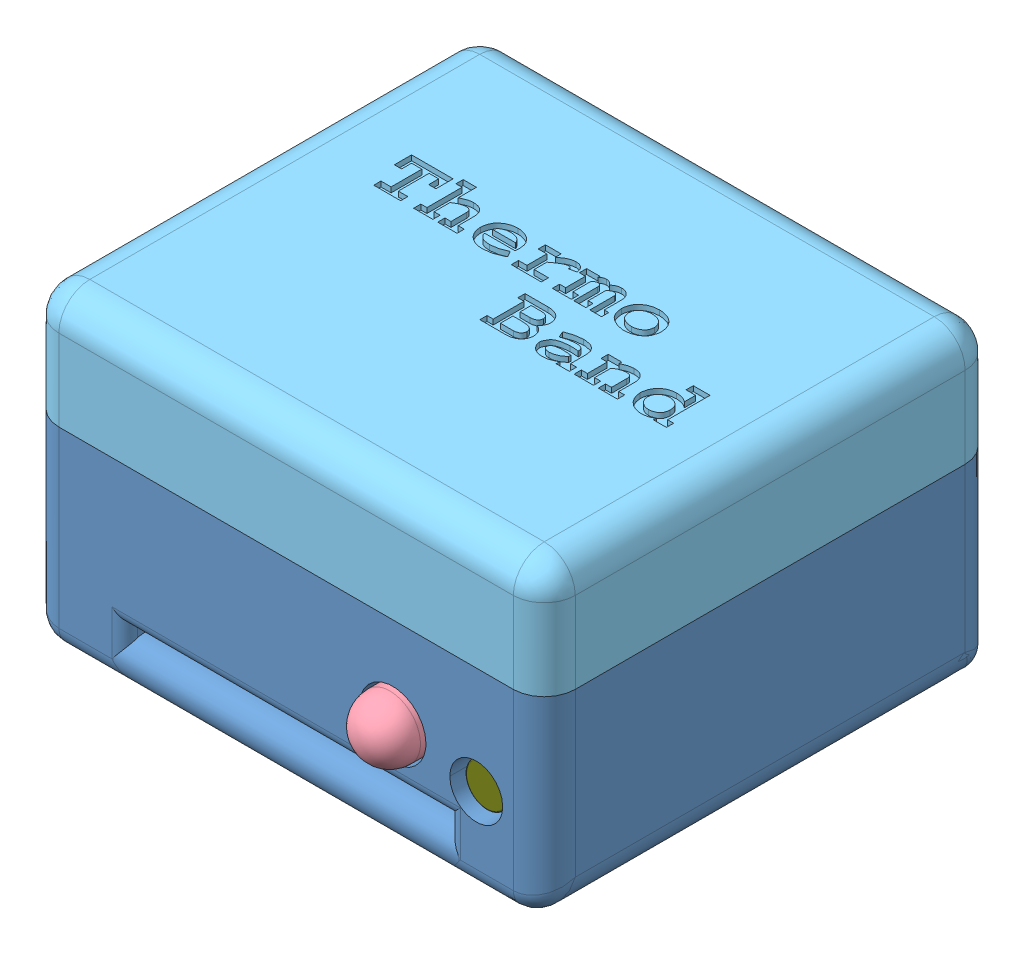
SolidWorks assembly Assembly, configuration Default. Lengths in mm.
Overall size (40 24.24 37.6).
114 component instances, 28 part files, 12 mates.
Components (placement in the parent):
- Housing-1: Housing [Default] at origin size (40 17 35.02)
- DS18B20-1: DS18B20 [Default] at (2.1825 -0.25 0.0476) x (0 0 -1) z (0 1 0) size (4.58 19.05 3.56)
- Battery-1: Battery [Default] at (-0.5 5.02 -1.5) size (35 8 20)
- Circuit Assembly-1: Circuit Assembly [Default] at (-15.4099 -5.9263 -30.8091) x (1 0 0) z (0 0 1) size (37.22 34.92 34.2)
  - PowerBoard.step-1: PowerBoard.step [Default] at (-2.5901 17.3095 38.1523) x (1 0 0) z (0 1 0) size (37.14 20 34.92)
    - Board_Power.step-1: Board_Power.step [Default] at origin size (36 20 0.91)
      - Open CASCADE STEP translator 7.5 1.1.1.step-1: Open CASCADE STEP translator 7.5 1.1.1.step [Default] at (0 0 -0.9132) size (36 20 0.91)
    - V1_Power.step-1: V1_Power.step [Default] at origin size (2.8 2.9 1.45)
      - 6479615344.step-1: 6479615344.step [Default] at (29.07 5.49 -0.9132) x (1 0 0) z (0 1 0) size (2.8 1.45 2.9)
    - R9_Power.step-1: R9_Power.step [Default] at origin size (1.45 2.15 0.71)
      - RES_CRGCQ0805F1K2_TEC.step-1: RES_CRGCQ0805F1K2_TEC.step [Default] at (33.56 5.72 -0.9132) x (0 1 0) z (0 0 -1) size (2.15 1.45 0.71)
    - C6_Power.step-1: C6_Power.step [Default] at origin size (2.15 1.45 0.71)
      - RES_CRGCQ0805F1K2_TEC.step-1: RES_CRGCQ0805F1K2_TEC.step [Default] at (28.99 2.19 -0.9132) x (-1 0 0) z (0 0 -1) size (2.15 1.45 0.71)
    - C5_Power.step-1: C5_Power.step [Default] at origin size (2.15 1.45 0.71)
      - RES_CRGCQ0805F1K2_TEC.step-1: RES_CRGCQ0805F1K2_TEC.step [Default] at (32.72 1.75 -0.9132) x (-1 0 0) z (0 0 -1) size (2.15 1.45 0.71)
    - P1_Power.step-1: P1_Power.step [Default] at origin size (6.87 8.94 4.22)
      - USB Connector Type C female 6pin.step-1: USB Connector Type C female 6pin.step [Default] at (-1.142 5.41 1.618) x (0 -1 0) z (-1 0 0) size (8.94 4.22 6.87)
    - Q1_Power.step-1: Q1_Power.step [Default] at origin size (10.41 4.45 29.34) (hidden)
      - 6479615824.step-1: 6479615824.step [Default] at (30.19 17.34 0) x (1 0 0) z (0 -1 0) size (10.41 29.34 4.45)
        - IRF9540N.step-1: IRF9540N.step [Default] at (-2.54 0 0.8128) size (10.41 29.34 4.45)
    - H2_Power.step-1: H2_Power.step [Default] at origin size (10.16 10.22 4.7)
      - 10129379-904002BLF.step-1: 10129379-904002BLF.step [Default] at (26.56 8.431 1.2177) x (0 -1 0) z (0 0 -1) size (10.22 10.16 4.7)
    - R8_Power.step-1: R8_Power.step [Default] at origin size (2.15 1.45 0.71)
      - RES_CRGCQ0805F1K2_TEC.step-1: RES_CRGCQ0805F1K2_TEC.step [Default] at (29.3 13.35 0) x (-1 0 0) z (0 0 1) size (2.15 1.45 0.71)
    - R7_Power.step-1: R7_Power.step [Default] at origin size (1.45 2.15 0.71)
      - RES_CRGCQ0805F1K2_TEC.step-1: RES_CRGCQ0805F1K2_TEC.step [Default] at (14.4 12.165 0) x (0 1 0) z (0 0 1) size (2.15 1.45 0.71)
    - R6_Power.step-1: R6_Power.step [Default] at origin size (1.45 2.15 0.71)
      - RES_CRGCQ0805F1K2_TEC.step-1: RES_CRGCQ0805F1K2_TEC.step [Default] at (23.1 17.5 0) x (0 1 0) z (0 0 1) size (2.15 1.45 0.71)
    - R5_Power.step-1: R5_Power.step [Default] at origin size (2.15 1.45 0.71)
      - RES_CRGCQ0805F1K2_TEC.step-1: RES_CRGCQ0805F1K2_TEC.step [Default] at (16.6 1.8 0) size (2.15 1.45 0.71)
    - R4_Power.step-1: R4_Power.step [Default] at origin size (2.15 1.45 0.71)
      - RES_CRGCQ0805F1K2_TEC.step-1: RES_CRGCQ0805F1K2_TEC.step [Default] at (8.28 10.59 -0.9132) x (-1 0 0) z (0 0 -1) size (2.15 1.45 0.71)
    - R3_Power.step-1: R3_Power.step [Default] at origin size (1.45 2.15 0.71)
      - RES_CRGCQ0805F1K2_TEC.step-1: RES_CRGCQ0805F1K2_TEC.step [Default] at (5.8 14.835 0) x (0 1 0) z (0 0 1) size (2.15 1.45 0.71)
    - R2_Power.step-1: R2_Power.step [Default] at origin size (1.45 2.15 0.71)
      - RES_CRGCQ0805F1K2_TEC.step-1: RES_CRGCQ0805F1K2_TEC.step [Default] at (8 14.865 0) x (0 1 0) z (0 0 1) size (2.15 1.45 0.71)
    - R1_Power.step-1: R1_Power.step [Default] at origin size (1.45 2.15 0.71)
      - RES_CRGCQ0805F1K2_TEC.step-1: RES_CRGCQ0805F1K2_TEC.step [Default] at (14.6 8.4 0) x (0 1 0) z (0 0 1) size (2.15 1.45 0.71)
    - Q3_Power.step-1: Q3_Power.step [Default] at origin size (4.76 3.63 20.95) (hidden)
      - 6470186752.step-1: 6470186752.step [Default] at (18.7734 17.507 0) x (1 0 0) z (0 -1 0) size (4.76 20.95 3.63)
        - KSC1008YBU_KSC1008YBU.step-1: KSC1008YBU_KSC1008YBU.step [Default] at (0 0 0.38) size (4.76 20.95 3.63)
    - Q2_Power.step-1: Q2_Power.step [Default] at origin size (4.76 3.63 20.95) (hidden)
      - 6470186672.step-1: 6470186672.step [Default] at (18.1966 12.903 0) x (-1 0 0) z (0 1 0) size (4.76 20.95 3.63)
        - KSC1008YBU_KSC1008YBU-0.step-1: KSC1008YBU_KSC1008YBU-0.step [Default] at (0 0 0.38) size (4.76 20.95 3.63)
    - M1_Power.step-1: M1_Power.step [Default] at origin size (3 4.5 1.05)
      - 6667053168.step-1: 6667053168.step [Default] at (22.835 8.51 0.15) size (3 4.5 1.05)
        - Extruded.step-1: Extruded.step [Default] at origin size (3 4.5 1.05)
    - IC2_Power.step-1: IC2_Power.step [Default] at origin size (1.8 3.1 1.3)
      - 6667052928.step-1: 6667052928.step [Default] at (18.025 8.6 0.15) size (1.8 3.1 1.3)
        - Extruded-1.step-1: Extruded-1.step [Default] at origin size (1.8 3.1 1.3)
    - IC1_Power.step-1: IC1_Power.step [Default] at origin size (4.33 4.9 1.1)
      - 6470186912.step-1: 6470186912.step [Default] at (11 14.85 0) x (0 1 0) z (0 0 1) size (4.9 4.33 1.1)
        - Body.step-1: Body.step [Default] at (-1.55 -1.55 0) size (3.1 3.1 0.95)
          - Open CASCADE STEP translator 7.5 1.2.1.step-1: Open CASCADE STEP translator 7.5 1.2.1.step [Default] at origin size (3.1 3.1 0.95)
        - Open CASCADE STEP translator 7.5 1.1.step-1: Open CASCADE STEP translator 7.5 1.1.step [Default] at (-1.55 -1.55 0.001) size (0.4 0.4 0.01)
        - Leader.step-1: Leader.step [Default] at (-1.55 -0.975 0) x (-1 0 0) z (0 0 1) size (1.25 0.32 1.05)
        - Leader.step-2: Leader.step [Default] at (-1.55 -0.325 0) x (-1 0 0) z (0 0 1) size (1.25 0.32 1.05)
        - Leader.step-3: Leader.step [Default] at (-1.55 0.325 0) x (-1 0 0) z (0 0 1) size (1.25 0.32 1.05)
        - Leader.step-4: Leader.step [Default] at (-1.55 0.975 0) x (-1 0 0) z (0 0 1) size (1.25 0.32 1.05)
        - Leader.step-5: Leader.step [Default] at (1.55 -0.975 0) size (1.25 0.32 1.05)
        - Leader.step-6: Leader.step [Default] at (1.55 -0.325 0) size (1.25 0.32 1.05)
        - Leader.step-7: Leader.step [Default] at (1.55 0.325 0) size (1.25 0.32 1.05)
        - Leader.step-8: Leader.step [Default] at (1.55 0.975 0) size (1.25 0.32 1.05)
    - C4_Power.step-1: C4_Power.step [Default] at origin size (1.45 2.15 0.71)
      - RES_CRGCQ0805F1K2_TEC.step-1: RES_CRGCQ0805F1K2_TEC.step [Default] at (8.14 7.57 -0.9132) x (0 1 0) z (0 0 -1) size (2.15 1.45 0.71)
    - C3_Power.step-1: C3_Power.step [Default] at origin size (2.59 3.99 8.21)
      - K104K15X7RF5TL2_VIS.step-1: K104K15X7RF5TL2_VIS.step [Default] at (8.05 2.314 0.3048) x (0 1 0) z (0 0 1) size (3.99 2.59 8.21)
    - C2_Power.step-1: C2_Power.step [Default] at origin size (1.45 2.15 0.71)
      - RES_CRGCQ0805F1K2_TEC.step-1: RES_CRGCQ0805F1K2_TEC.step [Default] at (12.08 2.09 -0.9132) x (0 1 0) z (0 0 -1) size (2.15 1.45 0.71)
    - C1_Power.step-1: C1_Power.step [Default] at origin size (2.59 3.99 8.21)
      - K104K15X7RF5TL2_VIS.step-1: K104K15X7RF5TL2_VIS.step [Default] at (11.8 5.254 0.3048) x (0 1 0) z (0 0 1) size (3.99 2.59 8.21)
  - SensorPCB.step-1: SensorPCB.step [Default] at (-2.5091 6.1912 41.4964) x (1 0 0) z (0 0 1) size (35.93 17.82 18.09)
    - Board_Sensor.step-1: Board_Sensor.step [Default] at origin size (28.7 17.82 0.91)
      - Open CASCADE STEP translator 7.5 2.1.1.step-1: Open CASCADE STEP translator 7.5 2.1.1.step [Default] at (0 0 -0.9132) size (28.7 17.82 0.91)
    - S2_Sensor.step-1: S2_Sensor.step [Default] at origin size (6 7.9 9.5)
      - 7413577248.step-1: 7413577248.step [Default] at (32.65 4.45 0) x (0 -1 0) z (-1 0 0) size (7.9 9.5 6)
    - S1_Sensor.step-1: S1_Sensor.step [Default] at origin size (3 4.5 1.05)
      - 6479614144.step-1: 6479614144.step [Default] at (12.34 9.02 -2.0132) size (3 4.5 1.05)
        - Extruded.step-1: Extruded.step [Default] at origin size (3 4.5 1.05)
    - IC1_Sensor.step-1: IC1_Sensor.step [Default] at origin size (24 16 3.17)
      - ESP-12F--3DModel-STEP-305423.step-1: ESP-12F--3DModel-STEP-305423.step [Default] at (12.065 8.854 -0.0223) x (1 0 0) z (0 -1 0) size (24 3.17 16)
        - Board.step-1: Board.step [Default] at origin size (24 0.87 16)
        - Shield.step-1: Shield.step [Default] at (3.2 3.17 0) x (1 0 0) z (0 0 -1) size (15.01 2.3 12.11)
        - LED-0603H0.75.step-1: LED-0603H0.75.step [Default] at (-5.5 0.87 -5.3) x (0 0 -1) z (0 1 0) size (1.7 0.9 0.75)
    - H2_Sensor.step-1: H2_Sensor.step [Default] at origin size (10.67 2.54 11.71)
      - PPPC041LFBN-RC.step-1: PPPC041LFBN-RC.step [Default] at (30.35 12.29 -0.926) x (1 0 0) z (0 1 0) size (10.67 11.71 2.54)
        - PPPC021LFBN-RC_C04.step-1: PPPC021LFBN-RC_C04.step [Default] at origin size (10.67 8.51 2.54)
        - Pin - Gold.step-1: Pin - Gold.step [Default] at (-3.81 0 0) size (0.76 3.71 0.41)
        - Pin - Gold.step-2: Pin - Gold.step [Default] at (-1.27 0 0) size (0.76 3.71 0.41)
        - Pin - Gold.step-3: Pin - Gold.step [Default] at (1.27 0 0) size (0.76 3.71 0.41)
        - Pin - Gold.step-4: Pin - Gold.step [Default] at (3.81 0 0) size (0.76 3.71 0.41)
    - R7_Sensor.step-1: R7_Sensor.step [Default] at origin size (1.45 2.15 0.71)
      - RES_CRGCQ0805F1K2_TEC.step-1: RES_CRGCQ0805F1K2_TEC.step [Default] at (17.1 9.6 -0.9132) x (0 1 0) z (0 0 -1) size (2.15 1.45 0.71)
    - R6_Sensor.step-1: R6_Sensor.step [Default] at origin size (2.15 1.45 0.71)
      - RES_CRGCQ0805F1K2_TEC.step-1: RES_CRGCQ0805F1K2_TEC.step [Default] at (22.3 3.8 -0.9132) x (-1 0 0) z (0 0 -1) size (2.15 1.45 0.71)
    - R5_Sensor.step-1: R5_Sensor.step [Default] at origin size (2.15 1.45 0.71)
      - RES_CRGCQ0805F1K2_TEC.step-1: RES_CRGCQ0805F1K2_TEC.step [Default] at (21.3 6.6 -0.9132) x (-1 0 0) z (0 0 -1) size (2.15 1.45 0.71)
    - R4_Sensor.step-1: R4_Sensor.step [Default] at origin size (2.15 1.45 0.71)
      - RES_CRGCQ0805F1K2_TEC.step-1: RES_CRGCQ0805F1K2_TEC.step [Default] at (21.2 9.3 -0.9132) x (-1 0 0) z (0 0 -1) size (2.15 1.45 0.71)
    - R3_Sensor.step-1: R3_Sensor.step [Default] at origin size (2.15 1.45 0.71)
      - RES_CRGCQ0805F1K2_TEC.step-1: RES_CRGCQ0805F1K2_TEC.step [Default] at (13.965 13.1 -0.9132) x (-1 0 0) z (0 0 -1) size (2.15 1.45 0.71)
    - R2_Sensor.step-1: R2_Sensor.step [Default] at origin size (2.15 1.45 0.71)
      - RES_CRGCQ0805F1K2_TEC.step-1: RES_CRGCQ0805F1K2_TEC.step [Default] at (22.235 13 -0.9132) x (-1 0 0) z (0 0 -1) size (2.15 1.45 0.71)
    - R1_Sensor.step-1: R1_Sensor.step [Default] at origin size (2.15 1.45 0.71)
      - RES_CRGCQ0805F1K2_TEC.step-1: RES_CRGCQ0805F1K2_TEC.step [Default] at (11.5 5 -0.9132) x (-1 0 0) z (0 0 -1) size (2.15 1.45 0.71)
    - H1_Sensor.step-1: H1_Sensor.step [Default] at origin size (7.62 2.54 11.68) (hidden)
      - M20-9990345_asm.step-1: M20-9990345_asm.step [Default] at (34.43 15.83 2.5526) x (-1 0 0) z (0 1 0) size (7.62 11.68 2.54)
        - M20-9990345_asm-1.step-1: M20-9990345_asm-1.step [Default] at origin size (7.62 11.68 2.54)
          - M20-999-MOULD.step-1: M20-999-MOULD.step [Default] at origin size (7.62 2.54 2.54)
          - M20-999-PIN.step-1: M20-999-PIN.step [Default] at (2.54 -5.58 0) x (1 0 0) z (0 0 -1) size (0.64 11.68 0.64)
          - M20-999-PIN.step-2: M20-999-PIN.step [Default] at (5.08 -5.58 0) x (1 0 0) z (0 0 -1) size (0.64 11.68 0.64)
          - M20-999-PIN.step-3: M20-999-PIN.step [Default] at (7.62 -5.58 0) x (1 0 0) z (0 0 -1) size (0.64 11.68 0.64)
  - CA GRB LED 5mm-1: CA GRB LED 5mm [Default] at (23.6712 11.8953 42.3091) x (0 1 0) z (1 0 0) size (5.12 34.2 5.5)
- Housing cover-1: Housing cover [Default] at (0 19.7 0) size (40 8.7 35)
Mates (geometry in assembly coordinates):
- Coincident8: coincident: line of Housing-1 through (19.4912 0 -6.7873) axis (0 0 1); point of DS18B20-1
- Parallel1: parallel anti-aligned: plane of Housing-1 through (-18 -45.5079 -15.5) normal (1 0 0); plane of DS18B20-1 through (-2.3975 -0.25 0.0476) normal (-1 0 0)
- Parallel2: parallel aligned: plane of Housing-1 through (0 0 0) normal (0 1 0); plane of DS18B20-1 through (2.1825 1.02 0.0476) normal (0 1 0)
- Coincident14: coincident: plane of Housing-1 through (0 0 0) normal (0 1 0); line of DS18B20-1 through (-2.3975 0 2.3376) axis (0 0 -1)
- Coincident15: coincident anti-aligned: plane of DS18B20-1 through (2.1825 1.02 0.0476) normal (0 1 0); plane of Battery-1 through (-0.5 1.02 -1.5) normal (0 -1 0)
- Coincident16: coincident anti-aligned: plane of Housing-1 through (-18 -45.5079 -15.5) normal (1 0 0); plane of Battery-1 through (-18 9.02 8.5) normal (-1 0 0)
- Coincident17: coincident anti-aligned: plane of Housing-1 through (14.5 -49.5079 -11.5) normal (0 0 1); plane of Battery-1 through (-18 9.02 -11.5) normal (0 0 -1)
- Coincident18: coincident anti-aligned: plane of Housing-1 through (-18 -45.5079 -15.5) normal (1 0 0); plane of Circuit Assembly-1/PowerBoard.step-1/Board_Power.step-1/Open CASCADE STEP translator 7.5 1.1.1.step-1 through (-18 10.47 -12.6568) normal (-1 0 0)
- Coincident19: coincident anti-aligned: plane of Battery-1 through (-0.5 9.02 -1.5) normal (0 1 0); plane of Circuit Assembly-1/PowerBoard.step-1/V1_Power.step-1/6479615344.step-1 through (11.07 9.02 1.8532) normal (0 -1 0)
- Coincident27: coincident aligned: plane of Housing-1 through (-20 -2 17.5) normal (-1 0 0); plane of Housing cover-1 through (-20 13 17.5) normal (-1 0 0)
- Coincident29: coincident aligned: plane of Housing-1 through (-20 -2 -17.5) normal (0 0 -1); plane of Housing cover-1 through (-20 13 -17.5) normal (0 0 -1)
- Coincident46: coincident anti-aligned: plane of Housing-1 through (0 13 0) normal (0 1 0); plane of Housing cover-1 through (0 13 0) normal (0 -1 0)
